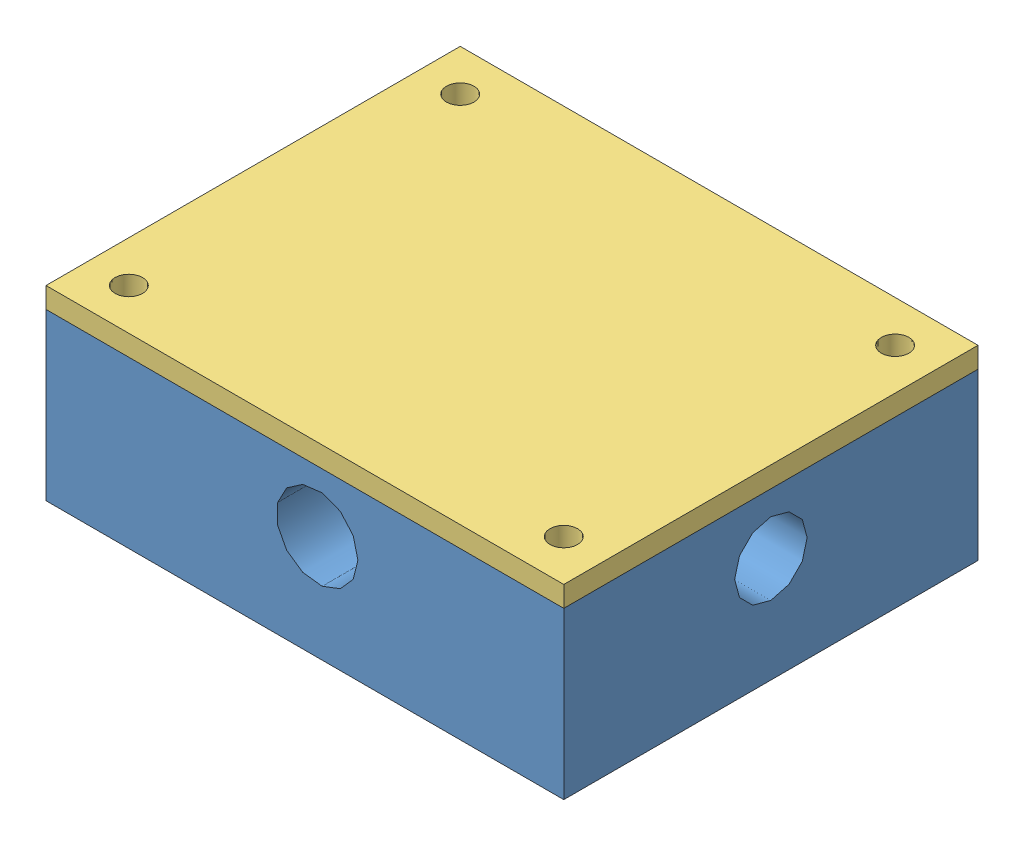
SolidWorks assembly SHT31_GLAND_ASSEMBLY, configuration Default. Lengths in mm.
Overall size (75 27 60).
3 component instances, 3 part files, 10 mates.
Components (placement in the parent):
- BaseSHT31_GLAND-1: BaseSHT31_GLAND [Default] at origin size (75 24 60)
- SHT31_GROVE-1: SHT31_GROVE [Default] at (17.1743 12 -19.917) size (41.8 6.7 23.6)
- TopSHT31_LID-1: TopSHT31_LID [Default] at (0 24 0) size (75 3 60)
Mates (geometry in assembly coordinates):
- Parallel1: parallel aligned: plane of BaseSHT31_GLAND-1 through (0 24 0) normal (0 0 1); plane of TopSHT31_LID-1 through (0 48 0) normal (0 0 1)
- Coincident1: coincident aligned: plane of BaseSHT31_GLAND-1 through (0 24 0) normal (0 0 1); plane of TopSHT31_LID-1 through (0 48 0) normal (0 0 1)
- Concentric1: concentric aligned: cylinder of BaseSHT31_GLAND-1 through (69 14 -6) axis (0 1 0) radius 1.75; cylinder of TopSHT31_LID-1 through (69 24 -6) axis (0 1 0) radius 2
- Coincident2: coincident anti-aligned: plane of BaseSHT31_GLAND-1 through (0 24 0) normal (0 1 0); plane of TopSHT31_LID-1 through (0 24 0) normal (0 -1 0)
- Coincident3: coincident anti-aligned: plane of BaseSHT31_GLAND-1 through (0 12 0) normal (0 1 0); plane of SHT31_GROVE-1 through (17.1743 12 -29.917) normal (0 -1 0)
- Parallel2: parallel aligned: plane of TopSHT31_LID-1 through (0 48 0) normal (0 1 0); plane of SHT31_GROVE-1 through (17.1743 12.7 -29.917) normal (0 1 0)
- Parallel3: parallel anti-aligned: plane of BaseSHT31_GLAND-1 through (61 7.75 -45) normal (-1 0 0); plane of SHT31_GROVE-1 through (55.1743 13.7 -35.917) normal (1 0 0)
- Coincident6: coincident anti-aligned: plane of BaseSHT31_GLAND-1 through (0 24 0) normal (0 1 0); plane of TopSHT31_LID-1 through (0 24 0) normal (0 -1 0)
- Concentric2: concentric anti-aligned: cylinder of BaseSHT31_GLAND-1 through (6 14 -54) axis (0 1 0) radius 1.75; cylinder of TopSHT31_LID-1 through (6 27 -54) axis (0 -1 0) radius 2
- Coincident7: coincident aligned: plane of BaseSHT31_GLAND-1 through (75 24 0) normal (1 0 0); plane of TopSHT31_LID-1 through (75 27 0) normal (1 0 0)
